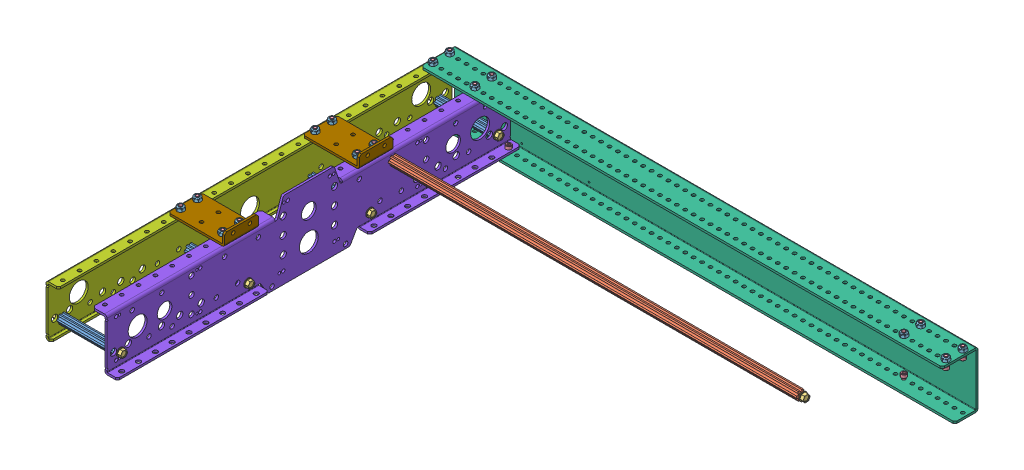
SolidWorks assembly AM14U3 Wide Frame Half, configuration Default. Lengths in mm.
Overall size (799.34 116.33 613.54).
56 component instances, 9 part files, 122 mates.
Components (placement in the parent):
- 500 Churro 3.375 in-1: 500 Churro 3.375 in [Default] at (-704.85 -61.341 539.242) x (0 0 1) z (-1 0 0) size (14.66 12.7 85.72)
- 500 Churro 3.375 in-2: 500 Churro 3.375 in [Default] at (-704.85 -66.929 346.837) x (0 0 1) z (-1 0 0) size (14.66 12.7 85.72)
- 500 Churro 3.375 in-3: 500 Churro 3.375 in [Default] at (-704.85 -66.929 162.687) x (0 0 1) z (-1 0 0) size (14.66 12.7 85.72)
- 500 Churro 3.375 in-4: 500 Churro 3.375 in [Default] at (-790.575 -61.341 -29.718) x (0 0 -1) z (1 0 0) size (14.66 12.7 85.72)
- 500 Churro 24.25 in-1: 500 Churro 24.25 in [Default] at (-85.725 -15.494 127.762) x (0 0 1) z (-1 0 0) size (14.66 12.7 615.95)
- 0.25-20 x 0.75 in Thread Rolling Screw-1: 0.25-20 x 0.75 in Thread Rolling Screw [FHTS 0.25-20-G-0.75-C] at (-701.675 -61.341 539.242) x (-1 0 0) z (0 0.924225 0.381849) size (24.64 12.19 12.19)
- 0.25-20 x 0.75 in Thread Rolling Screw-2: 0.25-20 x 0.75 in Thread Rolling Screw [FHTS 0.25-20-G-0.75-C] at (-701.675 -66.929 346.837) x (-1 0 0) z (0 0.924225 0.381849) size (24.64 12.19 12.19)
- 0.25-20 x 0.75 in Thread Rolling Screw-3: 0.25-20 x 0.75 in Thread Rolling Screw [FHTS 0.25-20-G-0.75-C] at (-701.675 -66.929 162.687) x (-1 0 0) z (0 0.924225 0.381849) size (24.64 12.19 12.19)
- 0.25-20 x 0.75 in Thread Rolling Screw-4: 0.25-20 x 0.75 in Thread Rolling Screw [FHTS 0.25-20-G-0.75-C] at (-701.675 -61.341 -29.718) x (-1 0 0) z (0 0.924225 0.381849) size (24.64 12.19 12.19)
- 0.25-20 x 0.75 in Thread Rolling Screw-5: 0.25-20 x 0.75 in Thread Rolling Screw [FHTS 0.25-20-G-0.75-C] at (-793.75 -61.341 -29.718) size (24.64 12.19 12.19)
- 0.25-20 x 0.75 in Thread Rolling Screw-6: 0.25-20 x 0.75 in Thread Rolling Screw [FHTS 0.25-20-G-0.75-C] at (-793.75 -66.929 162.687) size (24.64 12.19 12.19)
- 0.25-20 x 0.75 in Thread Rolling Screw-7: 0.25-20 x 0.75 in Thread Rolling Screw [FHTS 0.25-20-G-0.75-C] at (-704.85 -15.494 127.762) size (24.64 12.19 12.19)
- 0.25-20 x 0.75 in Thread Rolling Screw-8: 0.25-20 x 0.75 in Thread Rolling Screw [FHTS 0.25-20-G-0.75-C] at (-793.75 -66.929 346.837) size (24.64 12.19 12.19)
- 0.25-20 x 0.75 in Thread Rolling Screw-9: 0.25-20 x 0.75 in Thread Rolling Screw [FHTS 0.25-20-G-0.75-C] at (-793.75 -61.341 539.242) size (24.64 12.19 12.19)
- 0.25-20 x 0.75 in Thread Rolling Screw-10: 0.25-20 x 0.75 in Thread Rolling Screw [FHTS 0.25-20-G-0.75-C] at (-82.55 -15.494 127.762) x (-1 0 0) z (0 0.116139 -0.993233) size (24.64 12.19 12.19)
- 10-32 x 0.5 in SHCS Screw-19: 10-32 x 0.5 in SHCS Screw [HX-SHCS 0.19-32x1.375x1-C] at (-781.05 -11.43 -37.338) x (0 1 0) z (0 0 1) size (17.53 7.94 7.94)
- 10-32 x 0.5 in SHCS Screw-20: 10-32 x 0.5 in SHCS Screw [HX-SHCS 0.19-32x1.375x1-C] at (-781.05 -11.43 -11.938) x (0 1 0) z (0 0 1) size (17.53 7.94 7.94)
- 10-32 x 0.5 in SHCS Screw-21: 10-32 x 0.5 in SHCS Screw [HX-SHCS 0.19-32x1.375x1-C] at (-717.55 -11.43 -37.338) x (0 1 0) z (0 0 1) size (17.53 7.94 7.94)
- 10-32 x 0.5 in SHCS Screw-22: 10-32 x 0.5 in SHCS Screw [HX-SHCS 0.19-32x1.375x1-C] at (-717.55 -11.43 -11.938) x (0 1 0) z (0 0 1) size (17.53 7.94 7.94)
- 10-32 x 0.5 in SHCS Screw-23: 10-32 x 0.5 in SHCS Screw [HX-SHCS 0.19-32x1.375x1-C] at (-781.05 -11.43 140.462) x (0 1 0) z (0 0 1) size (17.53 7.94 7.94)
- 10-32 x 0.5 in SHCS Screw-24: 10-32 x 0.5 in SHCS Screw [HX-SHCS 0.19-32x1.375x1-C] at (-781.05 -11.43 165.862) x (0 1 0) z (0 0 1) size (17.53 7.94 7.94)
- 10-32 x 0.5 in SHCS Screw-25: 10-32 x 0.5 in SHCS Screw [HX-SHCS 0.19-32x1.375x1-C] at (-717.55 -11.43 140.462) x (0 1 0) z (0 0 1) size (17.53 7.94 7.94)
- 10-32 x 0.5 in SHCS Screw-26: 10-32 x 0.5 in SHCS Screw [HX-SHCS 0.19-32x1.375x1-C] at (-717.55 -11.43 165.862) x (0 1 0) z (0 0 1) size (17.53 7.94 7.94)
- 10-32 x 0.5 in SHCS Screw-27: 10-32 x 0.5 in SHCS Screw [HX-SHCS 0.19-32x1.375x1-C] at (-781.05 -11.43 343.662) x (0 1 0) z (0 0 1) size (17.53 7.94 7.94)
- 10-32 x 0.5 in SHCS Screw-28: 10-32 x 0.5 in SHCS Screw [HX-SHCS 0.19-32x1.375x1-C] at (-781.05 -11.43 369.062) x (0 1 0) z (0 0 1) size (17.53 7.94 7.94)
- 10-32 x 0.5 in SHCS Screw-29: 10-32 x 0.5 in SHCS Screw [HX-SHCS 0.19-32x1.375x1-C] at (-717.55 -11.43 343.662) x (0 1 0) z (0 0 1) size (17.53 7.94 7.94)
- 10-32 x 0.5 in SHCS Screw-30: 10-32 x 0.5 in SHCS Screw [HX-SHCS 0.19-32x1.375x1-C] at (-717.55 -11.43 369.062) x (0 1 0) z (0 0 1) size (17.53 7.94 7.94)
- 10-32 x 0.5 in SHCS Screw-31: 10-32 x 0.5 in SHCS Screw [HX-SHCS 0.19-32x1.375x1-C] at (-692.15 -73.152 -37.338) x (0 -1 0) z (0 0 1) size (17.53 7.94 7.94)
- 10-32 x 0.5 in SHCS Screw-32: 10-32 x 0.5 in SHCS Screw [HX-SHCS 0.19-32x1.375x1-C] at (-6.35 -11.176 -11.938) x (0 1 0) z (-0.461963 0 0.886899) size (17.53 7.94 7.94)
- 10-32 x 0.5 in SHCS Screw-33: 10-32 x 0.5 in SHCS Screw [HX-SHCS 0.19-32x1.375x1-C] at (-6.35 -11.176 -37.338) x (0 1 0) z (0 0 1) size (17.53 7.94 7.94)
- 10-32 x 0.5 in SHCS Screw-34: 10-32 x 0.5 in SHCS Screw [HX-SHCS 0.19-32x1.375x1-C] at (-69.85 -11.176 -11.938) x (0 1 0) z (0 0 1) size (17.53 7.94 7.94)
- 10-32 x 0.5 in SHCS Screw-35: 10-32 x 0.5 in SHCS Screw [HX-SHCS 0.19-32x1.375x1-C] at (-69.85 -11.176 -37.338) x (0 1 0) z (0 0 1) size (17.53 7.94 7.94)
- 10-32 x 0.5 in SHCS Screw-36: 10-32 x 0.5 in SHCS Screw [HX-SHCS 0.19-32x1.375x1-C] at (-95.25 -73.406 -37.338) x (0 -1 0) z (0.251234 0 0.967926) size (17.53 7.94 7.94)
- 10-32 Nylock Nut-19: 10-32 Nylock Nut [Default] at (-717.55 0 -11.938) x (1 0 0) z (0 1 0) size (10.18 11.01 7.1)
- 10-32 Nylock Nut-20: 10-32 Nylock Nut [Default] at (-717.55 0 -37.338) x (1 0 0) z (0 1 0) size (10.18 11.01 7.1)
- 10-32 Nylock Nut-21: 10-32 Nylock Nut [Default] at (-781.05 0 -11.938) x (1 0 0) z (0 1 0) size (10.18 11.01 7.1)
- 10-32 Nylock Nut-22: 10-32 Nylock Nut [Default] at (-781.05 0 -37.338) x (1 0 0) z (0 1 0) size (10.18 11.01 7.1)
- 10-32 Nylock Nut-23: 10-32 Nylock Nut [Default] at (-781.05 -0.254 140.462) x (1 0 0) z (0 1 0) size (10.18 11.01 7.1)
- 10-32 Nylock Nut-24: 10-32 Nylock Nut [Default] at (-781.05 -0.254 165.862) x (1 0 0) z (0 1 0) size (10.18 11.01 7.1)
- 10-32 Nylock Nut-25: 10-32 Nylock Nut [Default] at (-717.55 -0.254 140.462) x (1 0 0) z (0 1 0) size (10.18 11.01 7.1)
- 10-32 Nylock Nut-26: 10-32 Nylock Nut [Default] at (-717.55 -0.254 165.862) x (1 0 0) z (0 1 0) size (10.18 11.01 7.1)
- 10-32 Nylock Nut-27: 10-32 Nylock Nut [Default] at (-781.05 -0.254 343.662) x (1 0 0) z (0 1 0) size (10.18 11.01 7.1)
- 10-32 Nylock Nut-28: 10-32 Nylock Nut [Default] at (-781.05 -0.254 369.062) x (1 0 0) z (0 1 0) size (10.18 11.01 7.1)
- 10-32 Nylock Nut-29: 10-32 Nylock Nut [Default] at (-717.55 -0.254 343.662) x (1 0 0) z (0 1 0) size (10.18 11.01 7.1)
- 10-32 Nylock Nut-30: 10-32 Nylock Nut [Default] at (-717.55 -0.254 369.062) x (1 0 0) z (0 1 0) size (10.18 11.01 7.1)
- 10-32 Nylock Nut-31: 10-32 Nylock Nut [Default] at (-692.15 -84.582 -37.338) x (1 0 0) z (0 -1 0) size (10.18 11.01 7.1)
- 10-32 Nylock Nut-32: 10-32 Nylock Nut [Default] at (-95.25 -84.582 -37.338) x (1 0 0) z (0 -1 0) size (10.18 11.01 7.1)
- 10-32 Nylock Nut-33: 10-32 Nylock Nut [Default] at (-69.85 0 -11.938) x (1 0 0) z (0 1 0) size (10.18 11.01 7.1)
- 10-32 Nylock Nut-34: 10-32 Nylock Nut [Default] at (-69.85 0 -37.338) x (1 0 0) z (0 1 0) size (10.18 11.01 7.1)
- 10-32 Nylock Nut-35: 10-32 Nylock Nut [Default] at (-6.35 0 -37.338) x (1 0 0) z (0 1 0) size (10.18 11.01 7.1)
- 10-32 Nylock Nut-36: 10-32 Nylock Nut [Default] at (-6.35 0 -11.938) x (1 0 0) z (0 1 0) size (10.18 11.01 7.1)
- AM14U3 End Plate-1: AM14U3 End Plate [Default] at (-787.4 -81.407 -53.975) x (1 0 0) z (0 -1 0) size (787.4 53.98 84.58)
- AM14U3 Outer Plate_Wide-1: AM14U3 Outer Plate_Wide [Default] at (-769.3485 -27.0221 -29.1885) x (0 0 1) z (0 -1 0) size (609.6 19.05 77.72)
- AM14U3 Inner Plate_Wide-1: AM14U3 Inner Plate_Wide [Default] at (-713.7116 -19.2169 539.8409) x (0 0 -1) z (0 -1 0) size (609.6 38.1 116.33)
- Bracket 2x3 Hole Pattern-1: Bracket 2x3 Hole Pattern [Default] at (-787.4 -3.429 394.462) size (85.72 19.05 50.8)
- Bracket 2x3 Hole Pattern-2: Bracket 2x3 Hole Pattern [Default] at (-787.4 -3.429 191.262) size (85.72 19.05 50.8)
Mates (geometry in assembly coordinates):
- Coincident1: coincident aligned: plane of AM14U3 End Plate-1 through (0 0 0) normal (0 1 0); plane of assembly through (0 0 0) normal (0 1 0)
- Coincident2: coincident aligned: plane of AM14U3 End Plate-1 through (0 -81.407 -50.8) normal (1 0 0); plane of assembly through (0 0 0) normal (1 0 0)
- Coincident3: coincident aligned: plane of AM14U3 End Plate-1 through (0 0 0) normal (0 0 1); plane of assembly through (0 0 0) normal (0 0 1)
- Concentric1: concentric anti-aligned: cylinder of AM14U3 End Plate-1 through (-781.05 0 -37.338) axis (0 -1 0) radius 2.667; cylinder of AM14U3 Outer Plate_Wide-1 through (-781.05 -81.153 -37.338) axis (0 1 0) radius 2.667
- Concentric2: concentric aligned: cylinder of AM14U3 End Plate-1 through (-781.05 -5.08 -11.938) axis (0 1 0) radius 2.667; cylinder of AM14U3 Outer Plate_Wide-1 through (-781.05 -81.153 -11.938) axis (0 1 0) radius 2.667
- Coincident5: coincident anti-aligned: circle of AM14U3 End Plate-1; cylinder of AM14U3 Inner Plate_Wide-1 through (-717.55 -81.153 -37.338) axis (0 1 0) radius 2.667
- Concentric3: concentric aligned: cylinder of AM14U3 End Plate-1 through (-717.55 -5.08 -11.938) axis (0 1 0) radius 2.667; cylinder of AM14U3 Inner Plate_Wide-1 through (-717.55 -81.153 -11.938) axis (0 1 0) radius 2.667
- Distance2: distance = 0.254 mm anti-aligned: plane of AM14U3 Inner Plate_Wide-1 through (-704.85 -3.429 -151.638) normal (0 1 0); plane of AM14U3 End Plate-1 through (0 -3.175 0) normal (0 -1 0)
- Concentric4: concentric aligned: cylinder of AM14U3 Inner Plate_Wide-1 through (-717.55 -81.153 343.662) axis (0 1 0) radius 2.667; cylinder of Bracket 2x3 Hole Pattern-1 through (-717.55 -3.429 343.662) axis (0 1 0) radius 2.667
- Concentric5: concentric aligned: cylinder of AM14U3 Inner Plate_Wide-1 through (-717.55 -81.153 369.062) axis (0 1 0) radius 2.667; cylinder of Bracket 2x3 Hole Pattern-1 through (-717.55 -3.429 369.062) axis (0 1 0) radius 2.667
- Coincident7: coincident anti-aligned: plane of AM14U3 Inner Plate_Wide-1 through (-704.85 -3.429 -151.638) normal (0 1 0); plane of Bracket 2x3 Hole Pattern-1 through (-787.4 -3.429 330.962) normal (0 -1 0)
- Concentric6: concentric aligned: cylinder of AM14U3 Inner Plate_Wide-1 through (-717.55 -81.153 165.862) axis (0 1 0) radius 2.667; cylinder of Bracket 2x3 Hole Pattern-2 through (-717.55 -3.429 165.862) axis (0 1 0) radius 2.667
- Coincident8: coincident aligned: cylinder of AM14U3 Inner Plate_Wide-1 through (-717.55 -81.153 140.462) axis (0 1 0) radius 2.667; circle of Bracket 2x3 Hole Pattern-2
- Coincident9: coincident anti-aligned: plane of AM14U3 Inner Plate_Wide-1 through (-704.85 -3.429 -151.638) normal (0 1 0); plane of Bracket 2x3 Hole Pattern-2 through (-787.4 -3.429 127.762) normal (0 -1 0)
- Concentric43: concentric anti-aligned: cylinder of AM14U3 Outer Plate_Wide-1 through (-774.7 -61.341 539.242) axis (-1 0 0) radius 3.3528; cylinder of 500 Churro 3.375 in-1 through (-790.575 -61.341 539.242) axis (1 0 0) radius 2.9337
- Concentric44: concentric anti-aligned: cylinder of AM14U3 Outer Plate_Wide-1 through (-774.7 -61.341 -29.718) axis (-1 0 0) radius 3.3528; circle of 500 Churro 3.375 in-4
- Coincident46: coincident anti-aligned: plane of AM14U3 Outer Plate_Wide-1 through (-790.575 -7.366 -151.638) normal (1 0 0); plane of 500 Churro 3.375 in-4 through (-790.575 -58.166 -35.2173) normal (-1 0 0)
- Coincident47: coincident aligned: plane of AM14U3 Outer Plate_Wide-1 through (-790.575 -7.366 -151.638) normal (1 0 0); circle of 500 Churro 3.375 in-1
- Parallel1: parallel aligned: plane of AM14U3 Outer Plate_Wide-1 through (-790.575 -81.153 661.162) normal (0 -1 0); plane of 500 Churro 3.375 in-1 through (-790.575 -67.691 540.8295) normal (0 -1 0)
- Parallel2: parallel aligned: plane of AM14U3 Outer Plate_Wide-1 through (-790.575 -81.153 661.162) normal (0 -1 0); plane of 500 Churro 3.375 in-4 through (-704.85 -67.691 -26.0518) normal (0 -1 0)
- Concentric45: concentric anti-aligned: cylinder of AM14U3 Outer Plate_Wide-1 through (-774.7 -66.929 346.837) axis (-1 0 0) radius 3.3782; cylinder of 500 Churro 3.375 in-2 through (-790.575 -66.929 346.837) axis (1 0 0) radius 2.9337
- Concentric46: concentric anti-aligned: cylinder of AM14U3 Outer Plate_Wide-1 through (-774.7 -66.929 162.687) axis (-1 0 0) radius 3.3782; cylinder of 500 Churro 3.375 in-3 through (-790.575 -66.929 162.687) axis (1 0 0) radius 2.9337
- Coincident50: coincident anti-aligned: plane of AM14U3 Outer Plate_Wide-1 through (-790.575 -7.366 -151.638) normal (1 0 0); plane of 500 Churro 3.375 in-3 through (-790.575 -63.754 168.1863) normal (-1 0 0)
- Coincident51: coincident anti-aligned: plane of AM14U3 Outer Plate_Wide-1 through (-790.575 -7.366 -151.638) normal (1 0 0); plane of 500 Churro 3.375 in-2 through (-790.575 -63.754 352.3363) normal (-1 0 0)
- Concentric47: concentric anti-aligned: circle of AM14U3 Inner Plate_Wide-1; cylinder of 500 Churro 24.25 in-1 through (-701.675 -15.494 127.762) axis (1 0 0) radius 2.9337
- Coincident52: coincident anti-aligned: plane of AM14U3 Inner Plate_Wide-1 through (-701.675 -7.366 661.162) normal (1 0 0); plane of 500 Churro 24.25 in-1 through (-701.675 -12.319 133.2613) normal (-1 0 0)
- Parallel3: parallel aligned: plane of AM14U3 Inner Plate_Wide-1 through (-704.85 -3.429 -151.638) normal (0 1 0); plane of 500 Churro 24.25 in-1 through (-701.675 -9.144 126.1745) normal (0 1 0)
- Parallel4: parallel aligned: plane of AM14U3 Outer Plate_Wide-1 through (-790.575 -81.153 661.162) normal (0 -1 0); plane of 500 Churro 3.375 in-2 through (-790.575 -73.279 348.4245) normal (0 -1 0)
- Parallel5: parallel aligned: plane of AM14U3 Outer Plate_Wide-1 through (-790.575 -81.153 661.162) normal (0 -1 0); plane of 500 Churro 3.375 in-3 through (-790.575 -73.279 164.2745) normal (0 -1 0)
- Distance5: distance = 0.254 mm anti-aligned: plane of AM14U3 Outer Plate_Wide-1 through (-790.575 -3.429 661.162) normal (0 1 0); plane of AM14U3 End Plate-1 through (0 -3.175 0) normal (0 -1 0)
- Concentric481: concentric aligned: cylinder of AM14U3 Inner Plate_Wide-1 through (-723.9 -61.341 539.242) axis (1 0 0) radius 3.3528; cylinder of 0.25-20 x 0.75 in Thread Rolling Screw-1 through (-701.675 -61.341 539.242) axis (1 0 0) radius 3.175
- Coincident571: coincident anti-aligned: plane of AM14U3 Inner Plate_Wide-1 through (-701.675 -7.366 661.162) normal (1 0 0); plane of 0.25-20 x 0.75 in Thread Rolling Screw-1 through (-701.675 -62.5534 542.1764) normal (-1 0 0)
- Concentric491: concentric aligned: cylinder of AM14U3 Inner Plate_Wide-1 through (-723.9 -66.929 346.837) axis (1 0 0) radius 3.3528; cylinder of 0.25-20 x 0.75 in Thread Rolling Screw-2 through (-701.675 -66.929 346.837) axis (1 0 0) radius 3.175
- Coincident581: coincident anti-aligned: plane of AM14U3 Inner Plate_Wide-1 through (-701.675 -7.366 661.162) normal (1 0 0); plane of 0.25-20 x 0.75 in Thread Rolling Screw-2 through (-701.675 -68.1414 349.7714) normal (-1 0 0)
- Concentric501: concentric aligned: cylinder of AM14U3 Inner Plate_Wide-1 through (-723.9 -66.929 162.687) axis (1 0 0) radius 3.3528; cylinder of 0.25-20 x 0.75 in Thread Rolling Screw-3 through (-701.675 -66.929 162.687) axis (1 0 0) radius 3.175
- Coincident591: coincident anti-aligned: plane of AM14U3 Inner Plate_Wide-1 through (-701.675 -7.366 661.162) normal (1 0 0); plane of 0.25-20 x 0.75 in Thread Rolling Screw-3 through (-701.675 -68.1414 165.6214) normal (-1 0 0)
- Concentric511: concentric aligned: cylinder of AM14U3 Inner Plate_Wide-1 through (-723.9 -61.341 -29.718) axis (1 0 0) radius 3.3528; cylinder of 0.25-20 x 0.75 in Thread Rolling Screw-4 through (-701.675 -61.341 -29.718) axis (1 0 0) radius 3.175
- Coincident601: coincident anti-aligned: plane of AM14U3 Inner Plate_Wide-1 through (-701.675 -7.366 661.162) normal (1 0 0); plane of 0.25-20 x 0.75 in Thread Rolling Screw-4 through (-701.675 -62.5534 -26.7836) normal (-1 0 0)
- Concentric521: concentric aligned: cylinder of AM14U3 Outer Plate_Wide-1 through (-774.7 -61.341 -29.718) axis (-1 0 0) radius 3.3528; cylinder of 0.25-20 x 0.75 in Thread Rolling Screw-5 through (-793.75 -61.341 -29.718) axis (-1 0 0) radius 3.175
- Coincident611: coincident anti-aligned: plane of AM14U3 Outer Plate_Wide-1 through (-793.75 -7.366 -151.638) normal (-1 0 0); plane of 0.25-20 x 0.75 in Thread Rolling Screw-5 through (-793.75 -58.166 -29.718) normal (1 0 0)
- Concentric531: concentric aligned: cylinder of AM14U3 Outer Plate_Wide-1 through (-774.7 -66.929 162.687) axis (-1 0 0) radius 3.3782; cylinder of 0.25-20 x 0.75 in Thread Rolling Screw-6 through (-793.75 -66.929 162.687) axis (-1 0 0) radius 3.175
- Coincident621: coincident anti-aligned: plane of AM14U3 Outer Plate_Wide-1 through (-793.75 -7.366 -151.638) normal (-1 0 0); plane of 0.25-20 x 0.75 in Thread Rolling Screw-6 through (-793.75 -63.754 162.687) normal (1 0 0)
- Concentric541: concentric aligned: cylinder of AM14U3 Inner Plate_Wide-1 through (-685.8 -15.494 127.762) axis (-1 0 0) radius 3.3528; cylinder of 0.25-20 x 0.75 in Thread Rolling Screw-7 through (-704.85 -15.494 127.762) axis (-1 0 0) radius 3.175
- Coincident631: coincident anti-aligned: plane of AM14U3 Inner Plate_Wide-1 through (-704.85 -7.366 661.162) normal (-1 0 0); plane of 0.25-20 x 0.75 in Thread Rolling Screw-7 through (-704.85 -12.319 127.762) normal (1 0 0)
- Concentric551: concentric aligned: cylinder of AM14U3 Outer Plate_Wide-1 through (-774.7 -66.929 346.837) axis (-1 0 0) radius 3.3782; cylinder of 0.25-20 x 0.75 in Thread Rolling Screw-8 through (-793.75 -66.929 346.837) axis (-1 0 0) radius 3.175
- Coincident641: coincident anti-aligned: plane of AM14U3 Outer Plate_Wide-1 through (-793.75 -7.366 -151.638) normal (-1 0 0); plane of 0.25-20 x 0.75 in Thread Rolling Screw-8 through (-793.75 -63.754 346.837) normal (1 0 0)
- Concentric561: concentric aligned: cylinder of AM14U3 Outer Plate_Wide-1 through (-774.7 -61.341 539.242) axis (-1 0 0) radius 3.3528; cylinder of 0.25-20 x 0.75 in Thread Rolling Screw-9 through (-793.75 -61.341 539.242) axis (-1 0 0) radius 3.175
- Coincident651: coincident anti-aligned: plane of AM14U3 Outer Plate_Wide-1 through (-793.75 -7.366 -151.638) normal (-1 0 0); plane of 0.25-20 x 0.75 in Thread Rolling Screw-9 through (-793.75 -58.166 539.242) normal (1 0 0)
- Concentric57: concentric aligned: cylinder of 500 Churro 24.25 in-1 through (-701.675 -15.494 127.762) axis (1 0 0) radius 2.9337; cylinder of 0.25-20 x 0.75 in Thread Rolling Screw-10 through (-82.55 -15.494 127.762) axis (1 0 0) radius 3.175
- Distance6: distance = 3.175 mm anti-aligned: plane of 0.25-20 x 0.75 in Thread Rolling Screw-10 through (-82.55 -12.3405 128.1307) normal (-1 0 0); plane of 500 Churro 24.25 in-1 through (-85.725 -12.319 133.2613) normal (1 0 0)
- Concentric5621: concentric anti-aligned: cylinder of AM14U3 Outer Plate_Wide-1 through (-781.05 -81.153 -37.338) axis (0 1 0) radius 2.667; cylinder of 10-32 x 0.5 in SHCS Screw-19 through (-781.05 -43.18 -37.338) axis (0 -1 0) radius 3.9688
- Coincident6521: coincident anti-aligned: plane of AM14U3 Outer Plate_Wide-1 through (-790.575 -6.604 661.162) normal (0 -1 0); plane of 10-32 x 0.5 in SHCS Screw-19 through (-785.0187 -6.604 -37.338) normal (0 1 0)
- Concentric5631: concentric anti-aligned: cylinder of AM14U3 Outer Plate_Wide-1 through (-781.05 -81.153 -11.938) axis (0 1 0) radius 2.667; cylinder of 10-32 x 0.5 in SHCS Screw-20 through (-781.05 -43.18 -11.938) axis (0 -1 0) radius 3.9688
- Coincident6531: coincident anti-aligned: plane of AM14U3 Outer Plate_Wide-1 through (-790.575 -6.604 661.162) normal (0 -1 0); plane of 10-32 x 0.5 in SHCS Screw-20 through (-785.0187 -6.604 -11.938) normal (0 1 0)
- Concentric5641: concentric anti-aligned: cylinder of AM14U3 Inner Plate_Wide-1 through (-717.55 -81.153 -37.338) axis (0 1 0) radius 2.667; cylinder of 10-32 x 0.5 in SHCS Screw-21 through (-717.55 -43.18 -37.338) axis (0 -1 0) radius 3.9688
- Coincident6541: coincident anti-aligned: plane of AM14U3 Inner Plate_Wide-1 through (-704.85 -6.604 -151.638) normal (0 -1 0); plane of 10-32 x 0.5 in SHCS Screw-21 through (-721.5187 -6.604 -37.338) normal (0 1 0)
- Concentric5651: concentric anti-aligned: cylinder of AM14U3 Inner Plate_Wide-1 through (-717.55 -81.153 -11.938) axis (0 1 0) radius 2.667; cylinder of 10-32 x 0.5 in SHCS Screw-22 through (-717.55 -43.18 -11.938) axis (0 -1 0) radius 3.9688
- Coincident6551: coincident anti-aligned: plane of AM14U3 Inner Plate_Wide-1 through (-704.85 -6.604 -151.638) normal (0 -1 0); plane of 10-32 x 0.5 in SHCS Screw-22 through (-721.5187 -6.604 -11.938) normal (0 1 0)
- Concentric5661: concentric anti-aligned: cylinder of AM14U3 Outer Plate_Wide-1 through (-781.05 -81.153 140.462) axis (0 1 0) radius 2.667; cylinder of 10-32 x 0.5 in SHCS Screw-23 through (-781.05 -43.18 140.462) axis (0 -1 0) radius 3.9688
- Coincident6561: coincident anti-aligned: plane of AM14U3 Outer Plate_Wide-1 through (-790.575 -6.604 661.162) normal (0 -1 0); plane of 10-32 x 0.5 in SHCS Screw-23 through (-785.0187 -6.604 140.462) normal (0 1 0)
- Concentric5671: concentric anti-aligned: cylinder of AM14U3 Outer Plate_Wide-1 through (-781.05 -81.153 165.862) axis (0 1 0) radius 2.667; cylinder of 10-32 x 0.5 in SHCS Screw-24 through (-781.05 -43.18 165.862) axis (0 -1 0) radius 3.9688
- Coincident6571: coincident anti-aligned: plane of AM14U3 Outer Plate_Wide-1 through (-790.575 -6.604 661.162) normal (0 -1 0); plane of 10-32 x 0.5 in SHCS Screw-24 through (-785.0187 -6.604 165.862) normal (0 1 0)
- Concentric5681: concentric anti-aligned: cylinder of AM14U3 Inner Plate_Wide-1 through (-717.55 -81.153 140.462) axis (0 1 0) radius 2.667; cylinder of 10-32 x 0.5 in SHCS Screw-25 through (-717.55 -43.18 140.462) axis (0 -1 0) radius 3.9688
- Coincident6581: coincident anti-aligned: plane of AM14U3 Inner Plate_Wide-1 through (-704.85 -6.604 -151.638) normal (0 -1 0); plane of 10-32 x 0.5 in SHCS Screw-25 through (-721.5187 -6.604 140.462) normal (0 1 0)
- Concentric5691: concentric anti-aligned: cylinder of AM14U3 Inner Plate_Wide-1 through (-717.55 -81.153 165.862) axis (0 1 0) radius 2.667; cylinder of 10-32 x 0.5 in SHCS Screw-26 through (-717.55 -43.18 165.862) axis (0 -1 0) radius 3.9688
- Coincident6591: coincident anti-aligned: plane of AM14U3 Inner Plate_Wide-1 through (-704.85 -6.604 -151.638) normal (0 -1 0); plane of 10-32 x 0.5 in SHCS Screw-26 through (-721.5187 -6.604 165.862) normal (0 1 0)
- Concentric5701: concentric anti-aligned: cylinder of AM14U3 Outer Plate_Wide-1 through (-781.05 -81.153 343.662) axis (0 1 0) radius 2.667; cylinder of 10-32 x 0.5 in SHCS Screw-27 through (-781.05 -43.18 343.662) axis (0 -1 0) radius 3.9688
- Coincident6601: coincident anti-aligned: plane of AM14U3 Outer Plate_Wide-1 through (-790.575 -6.604 661.162) normal (0 -1 0); plane of 10-32 x 0.5 in SHCS Screw-27 through (-785.0187 -6.604 343.662) normal (0 1 0)
- Concentric5711: concentric anti-aligned: cylinder of AM14U3 Outer Plate_Wide-1 through (-781.05 -81.153 369.062) axis (0 1 0) radius 2.667; cylinder of 10-32 x 0.5 in SHCS Screw-28 through (-781.05 -43.18 369.062) axis (0 -1 0) radius 3.9688
- Coincident6611: coincident anti-aligned: plane of AM14U3 Outer Plate_Wide-1 through (-790.575 -6.604 661.162) normal (0 -1 0); plane of 10-32 x 0.5 in SHCS Screw-28 through (-785.0187 -6.604 369.062) normal (0 1 0)
- Concentric5721: concentric anti-aligned: cylinder of AM14U3 Inner Plate_Wide-1 through (-717.55 -81.153 343.662) axis (0 1 0) radius 2.667; cylinder of 10-32 x 0.5 in SHCS Screw-29 through (-717.55 -43.18 343.662) axis (0 -1 0) radius 3.9688
- Coincident6621: coincident anti-aligned: plane of AM14U3 Inner Plate_Wide-1 through (-704.85 -6.604 -151.638) normal (0 -1 0); plane of 10-32 x 0.5 in SHCS Screw-29 through (-721.5187 -6.604 343.662) normal (0 1 0)
- Concentric5731: concentric anti-aligned: cylinder of AM14U3 Inner Plate_Wide-1 through (-717.55 -81.153 369.062) axis (0 1 0) radius 2.667; cylinder of 10-32 x 0.5 in SHCS Screw-30 through (-717.55 -43.18 369.062) axis (0 -1 0) radius 3.9688
- Coincident6631: coincident anti-aligned: plane of AM14U3 Inner Plate_Wide-1 through (-704.85 -6.604 -151.638) normal (0 -1 0); plane of 10-32 x 0.5 in SHCS Screw-30 through (-721.5187 -6.604 369.062) normal (0 1 0)
- Concentric5741: concentric aligned: cylinder of AM14U3 Inner Plate_Wide-1 through (-692.15 -81.153 -37.338) axis (0 1 0) radius 3.3528; cylinder of 10-32 x 0.5 in SHCS Screw-31 through (-692.15 -41.402 -37.338) axis (0 1 0) radius 3.9688
- Coincident6641: coincident anti-aligned: plane of AM14U3 Inner Plate_Wide-1 through (-701.675 -77.978 -151.638) normal (0 1 0); plane of 10-32 x 0.5 in SHCS Screw-31 through (-688.1812 -77.978 -37.338) normal (0 -1 0)
- Concentric5751: concentric anti-aligned: cylinder of AM14U3 End Plate-1 through (-6.35 -5.08 -11.938) axis (0 1 0) radius 2.667; cylinder of 10-32 x 0.5 in SHCS Screw-32 through (-6.35 -42.926 -11.938) axis (0 -1 0) radius 3.9688
- Concentric5761: concentric aligned: cylinder of AM14U3 End Plate-1 through (-6.35 0 -37.338) axis (0 -1 0) radius 2.667; cylinder of 10-32 x 0.5 in SHCS Screw-33 through (-6.35 -42.926 -37.338) axis (0 -1 0) radius 3.9688
- Concentric5771: concentric anti-aligned: cylinder of AM14U3 End Plate-1 through (-69.85 -5.08 -11.938) axis (0 1 0) radius 2.667; cylinder of 10-32 x 0.5 in SHCS Screw-34 through (-69.85 -42.926 -11.938) axis (0 -1 0) radius 3.9688
- Concentric5781: concentric aligned: cylinder of AM14U3 End Plate-1 through (-69.85 0 -37.338) axis (0 -1 0) radius 2.667; cylinder of 10-32 x 0.5 in SHCS Screw-35 through (-69.85 -42.926 -37.338) axis (0 -1 0) radius 3.9688
- Concentric5791: concentric anti-aligned: cylinder of AM14U3 End Plate-1 through (-95.25 0 -37.338) axis (0 -1 0) radius 2.667; cylinder of 10-32 x 0.5 in SHCS Screw-36 through (-95.25 -41.656 -37.338) axis (0 1 0) radius 3.9688
- Concentric5801: concentric aligned: cylinder of AM14U3 End Plate-1 through (-717.55 -5.08 -11.938) axis (0 1 0) radius 2.667; cylinder of 10-32 Nylock Nut-19 through (-717.55 5.9531 -11.938) axis (0 1 0) radius 2.0193
- Coincident6701: coincident anti-aligned: plane of AM14U3 End Plate-1 through (0 0 0) normal (0 1 0); plane of 10-32 Nylock Nut-19 through (-717.55 0 -11.938) normal (0 -1 0)
- Concentric5811: concentric anti-aligned: cylinder of AM14U3 End Plate-1 through (-717.55 0 -37.338) axis (0 -1 0) radius 2.667; cylinder of 10-32 Nylock Nut-20 through (-717.55 5.9531 -37.338) axis (0 1 0) radius 2.0193
- Coincident6711: coincident anti-aligned: plane of AM14U3 End Plate-1 through (0 0 0) normal (0 1 0); plane of 10-32 Nylock Nut-20 through (-717.55 0 -37.338) normal (0 -1 0)
- Concentric5821: concentric aligned: cylinder of AM14U3 End Plate-1 through (-781.05 -5.08 -11.938) axis (0 1 0) radius 2.667; cylinder of 10-32 Nylock Nut-21 through (-781.05 5.9531 -11.938) axis (0 1 0) radius 2.0193
- Coincident6721: coincident anti-aligned: plane of AM14U3 End Plate-1 through (0 0 0) normal (0 1 0); plane of 10-32 Nylock Nut-21 through (-781.05 0 -11.938) normal (0 -1 0)
- Concentric5831: concentric anti-aligned: cylinder of AM14U3 End Plate-1 through (-781.05 0 -37.338) axis (0 -1 0) radius 2.667; cylinder of 10-32 Nylock Nut-22 through (-781.05 5.9531 -37.338) axis (0 1 0) radius 2.0193
- Coincident6731: coincident anti-aligned: plane of AM14U3 End Plate-1 through (0 0 0) normal (0 1 0); plane of 10-32 Nylock Nut-22 through (-781.05 0 -37.338) normal (0 -1 0)
- Concentric5841: concentric aligned: cylinder of Bracket 2x3 Hole Pattern-2 through (-781.05 -3.429 140.462) axis (0 1 0) radius 2.667; cylinder of 10-32 Nylock Nut-23 through (-781.05 5.6991 140.462) axis (0 1 0) radius 2.0193
- Coincident6741: coincident anti-aligned: plane of Bracket 2x3 Hole Pattern-2 through (-787.4 -0.254 127.762) normal (0 1 0); plane of 10-32 Nylock Nut-23 through (-781.05 -0.254 140.462) normal (0 -1 0)
- Concentric5851: concentric aligned: cylinder of Bracket 2x3 Hole Pattern-2 through (-781.05 -3.429 165.862) axis (0 1 0) radius 2.667; cylinder of 10-32 Nylock Nut-24 through (-781.05 5.6991 165.862) axis (0 1 0) radius 2.0193
- Coincident6751: coincident anti-aligned: plane of Bracket 2x3 Hole Pattern-2 through (-787.4 -0.254 127.762) normal (0 1 0); plane of 10-32 Nylock Nut-24 through (-781.05 -0.254 165.862) normal (0 -1 0)
- Concentric5861: concentric aligned: cylinder of Bracket 2x3 Hole Pattern-2 through (-717.55 -3.429 140.462) axis (0 1 0) radius 2.667; cylinder of 10-32 Nylock Nut-25 through (-717.55 5.6991 140.462) axis (0 1 0) radius 2.0193
- Coincident6761: coincident anti-aligned: plane of Bracket 2x3 Hole Pattern-2 through (-787.4 -0.254 127.762) normal (0 1 0); plane of 10-32 Nylock Nut-25 through (-717.55 -0.254 140.462) normal (0 -1 0)
- Concentric5871: concentric aligned: cylinder of Bracket 2x3 Hole Pattern-2 through (-717.55 -3.429 165.862) axis (0 1 0) radius 2.667; cylinder of 10-32 Nylock Nut-26 through (-717.55 5.6991 165.862) axis (0 1 0) radius 2.0193
- Coincident6771: coincident anti-aligned: plane of Bracket 2x3 Hole Pattern-2 through (-787.4 -0.254 127.762) normal (0 1 0); plane of 10-32 Nylock Nut-26 through (-717.55 -0.254 165.862) normal (0 -1 0)
- Concentric5881: concentric aligned: cylinder of Bracket 2x3 Hole Pattern-1 through (-781.05 -3.429 343.662) axis (0 1 0) radius 2.667; cylinder of 10-32 Nylock Nut-27 through (-781.05 5.6991 343.662) axis (0 1 0) radius 2.0193
- Coincident6781: coincident anti-aligned: plane of Bracket 2x3 Hole Pattern-1 through (-787.4 -0.254 330.962) normal (0 1 0); plane of 10-32 Nylock Nut-27 through (-781.05 -0.254 343.662) normal (0 -1 0)
- Concentric5891: concentric aligned: cylinder of Bracket 2x3 Hole Pattern-1 through (-781.05 -3.429 369.062) axis (0 1 0) radius 2.667; cylinder of 10-32 Nylock Nut-28 through (-781.05 5.6991 369.062) axis (0 1 0) radius 2.0193
- Coincident6791: coincident anti-aligned: plane of Bracket 2x3 Hole Pattern-1 through (-787.4 -0.254 330.962) normal (0 1 0); plane of 10-32 Nylock Nut-28 through (-781.05 -0.254 369.062) normal (0 -1 0)
- Concentric5901: concentric aligned: cylinder of Bracket 2x3 Hole Pattern-1 through (-717.55 -3.429 343.662) axis (0 1 0) radius 2.667; cylinder of 10-32 Nylock Nut-29 through (-717.55 5.6991 343.662) axis (0 1 0) radius 2.0193
- Coincident6801: coincident anti-aligned: plane of Bracket 2x3 Hole Pattern-1 through (-787.4 -0.254 330.962) normal (0 1 0); plane of 10-32 Nylock Nut-29 through (-717.55 -0.254 343.662) normal (0 -1 0)
- Concentric5911: concentric aligned: cylinder of Bracket 2x3 Hole Pattern-1 through (-717.55 -3.429 369.062) axis (0 1 0) radius 2.667; cylinder of 10-32 Nylock Nut-30 through (-717.55 5.6991 369.062) axis (0 1 0) radius 2.0193
- Coincident6811: coincident anti-aligned: plane of Bracket 2x3 Hole Pattern-1 through (-787.4 -0.254 330.962) normal (0 1 0); plane of 10-32 Nylock Nut-30 through (-717.55 -0.254 369.062) normal (0 -1 0)
- Concentric5921: concentric aligned: cylinder of AM14U3 End Plate-1 through (-692.15 0 -37.338) axis (0 -1 0) radius 2.667; cylinder of 10-32 Nylock Nut-31 through (-692.15 -90.5351 -37.338) axis (0 -1 0) radius 2.0193
- Coincident6821: coincident anti-aligned: plane of AM14U3 End Plate-1 through (-787.4 -84.582 -19.05) normal (0 -1 0); plane of 10-32 Nylock Nut-31 through (-692.15 -84.582 -37.338) normal (0 1 0)
- Concentric5931: concentric aligned: cylinder of AM14U3 End Plate-1 through (-95.25 0 -37.338) axis (0 -1 0) radius 2.667; cylinder of 10-32 Nylock Nut-32 through (-95.25 -90.5351 -37.338) axis (0 -1 0) radius 2.0193
- Coincident6831: coincident anti-aligned: plane of AM14U3 End Plate-1 through (-787.4 -84.582 -19.05) normal (0 -1 0); plane of 10-32 Nylock Nut-32 through (-95.25 -84.582 -37.338) normal (0 1 0)
- Concentric5941: concentric aligned: cylinder of AM14U3 End Plate-1 through (-69.85 -5.08 -11.938) axis (0 1 0) radius 2.667; cylinder of 10-32 Nylock Nut-33 through (-69.85 5.9531 -11.938) axis (0 1 0) radius 2.0193
- Coincident6841: coincident anti-aligned: plane of AM14U3 End Plate-1 through (0 0 0) normal (0 1 0); plane of 10-32 Nylock Nut-33 through (-69.85 0 -11.938) normal (0 -1 0)
- Concentric5951: concentric anti-aligned: cylinder of AM14U3 End Plate-1 through (-69.85 0 -37.338) axis (0 -1 0) radius 2.667; cylinder of 10-32 Nylock Nut-34 through (-69.85 5.9531 -37.338) axis (0 1 0) radius 2.0193
- Coincident6851: coincident anti-aligned: plane of AM14U3 End Plate-1 through (0 0 0) normal (0 1 0); plane of 10-32 Nylock Nut-34 through (-69.85 0 -37.338) normal (0 -1 0)
- Concentric5961: concentric anti-aligned: cylinder of AM14U3 End Plate-1 through (-6.35 0 -37.338) axis (0 -1 0) radius 2.667; cylinder of 10-32 Nylock Nut-35 through (-6.35 5.9531 -37.338) axis (0 1 0) radius 2.0193
- Coincident6861: coincident anti-aligned: plane of AM14U3 End Plate-1 through (0 0 0) normal (0 1 0); plane of 10-32 Nylock Nut-35 through (-6.35 0 -37.338) normal (0 -1 0)
- Concentric5971: concentric aligned: cylinder of AM14U3 End Plate-1 through (-6.35 -5.08 -11.938) axis (0 1 0) radius 2.667; cylinder of 10-32 Nylock Nut-36 through (-6.35 5.9531 -11.938) axis (0 1 0) radius 2.0193
- Coincident6871: coincident anti-aligned: plane of AM14U3 End Plate-1 through (0 0 0) normal (0 1 0); plane of 10-32 Nylock Nut-36 through (-6.35 0 -11.938) normal (0 -1 0)
- Coincident688: coincident aligned: plane of 10-32 x 0.5 in SHCS Screw-34 through (-71.7906 6.35 -11.938) normal (0 1 0); plane of 10-32 x 0.5 in SHCS Screw-35 through (-71.7906 6.35 -37.338) normal (0 1 0)
- Coincident689: coincident aligned: plane of 10-32 x 0.5 in SHCS Screw-33 through (-8.2906 6.35 -37.338) normal (0 1 0); plane of 10-32 x 0.5 in SHCS Screw-35 through (-71.7906 6.35 -37.338) normal (0 1 0)
- Coincident690: coincident aligned: plane of 10-32 x 0.5 in SHCS Screw-32 through (-8.0711 6.35 -12.8345) normal (0 1 0); plane of 10-32 x 0.5 in SHCS Screw-33 through (-8.2906 6.35 -37.338) normal (0 1 0)
- Distance7: distance = 3.175 mm anti-aligned: plane of 10-32 x 0.5 in SHCS Screw-32 through (-9.8699 -6.35 -13.7714) normal (0 1 0); plane of AM14U3 End Plate-1 through (0 -3.175 0) normal (0 -1 0)
- Distance8: distance = 3.175 mm anti-aligned: plane of AM14U3 End Plate-1 through (-787.4 -81.407 -19.05) normal (0 1 0); plane of 10-32 x 0.5 in SHCS Screw-36 through (-91.4085 -78.232 -38.3351) normal (0 -1 0)
